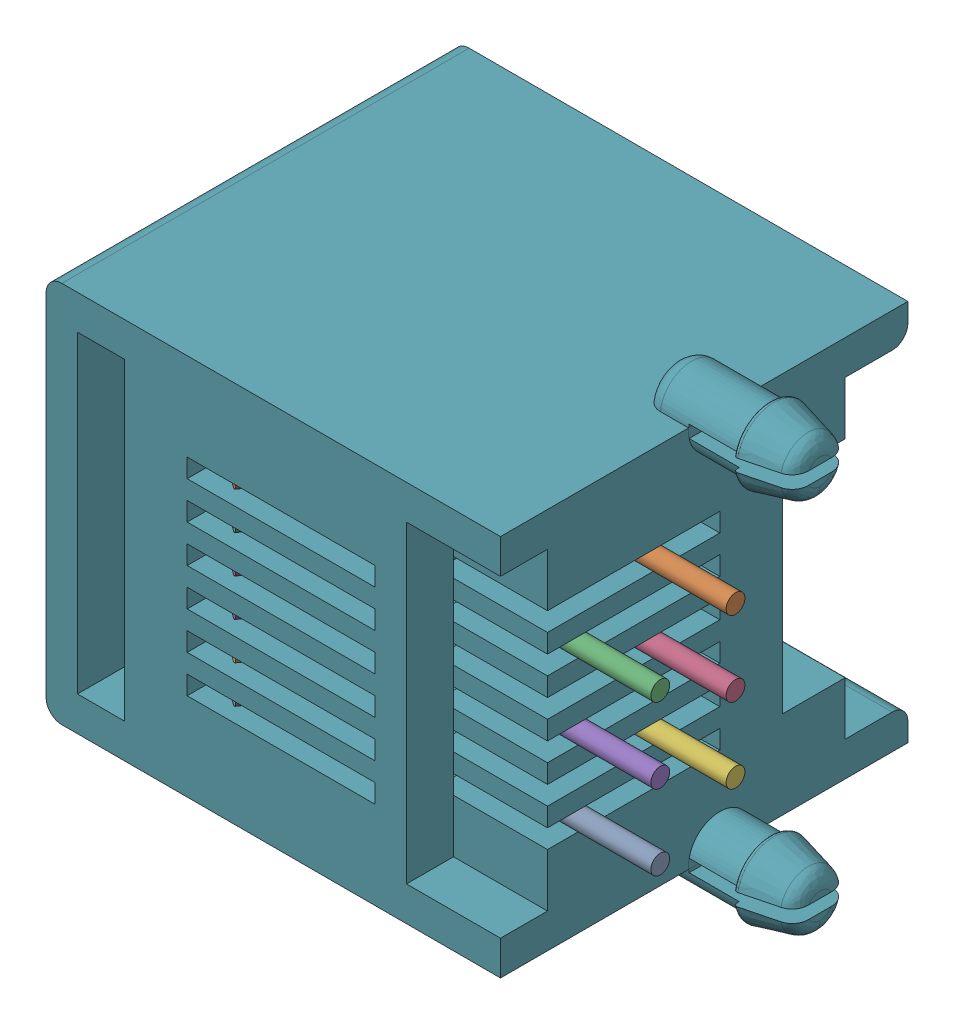
SolidWorks assembly RJ12 v2, configuration RJ12 v2. Lengths in mm.
Overall size (17.7 14.34 13).
7 component instances, 7 part files, 0 mates.
Components (placement in the parent):
- Fusion011-1: Fusion011 [Fusion011] at (21.75 14.2 -49.5) x (0 -1 0) z (-1 0 0) size (0.6 8.66 11.78)
- Fusion010-1: Fusion010 [Fusion010] at (21.75 21.4 -49.5) x (0 -1 0) z (-1 0 0) size (0.6 8.66 11.78)
- Fusion009-1: Fusion009 [Fusion009] at (21.75 19 -49.5) x (0 -1 0) z (-1 0 0) size (0.6 8.66 11.78)
- Fusion008-1: Fusion008 [Fusion008] at (21.75 19 -49.5) x (0 -1 0) z (-1 0 0) size (0.6 8.66 11.78)
- Fusion007-1: Fusion007 [Fusion007] at (21.75 16.6 -49.5) x (0 -1 0) z (-1 0 0) size (0.6 8.66 11.78)
- Fusion006-1: Fusion006 [Fusion006] at (21.75 16.6 -49.5) x (0 -1 0) z (-1 0 0) size (0.6 8.66 11.78)
- Fusion005-1: Fusion005 [Fusion005] at (21.75 16.6 -49.5) x (0 -1 0) z (-1 0 0) size (14.34 13 17.7)
